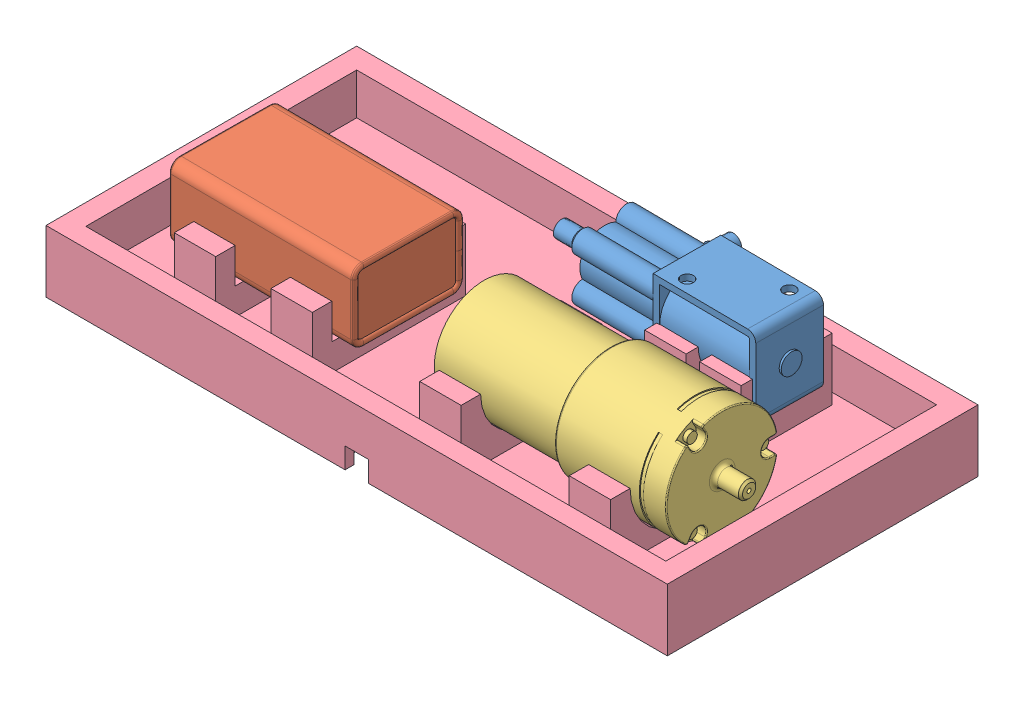
SolidWorks assembly Component_Holder_Assembly, configuration Default. Lengths in mm.
Overall size (150 33.4 75).
4 component instances, 4 part files, 0 mates.
Components (placement in the parent):
- Solenoid-1: Solenoid [Default] at (-18.5853 34.8731 -17.2665) x (0.000076 -1 0.000076) z (0.008726 -0.000076 -0.999962) size (20 56 26.1)
- Studio-R4 CAD Props_Battery-9v-1: Studio-R4 CAD Props_Battery-9v [Default] at (-69.16 35.0714 11.7328) x (0.008726 -0.000076 -0.999962) z (0 1 -0.000076) size (26.6 48.5 17.6)
- model.step-1: model.step [Default] at (6.8477 34.8616 14.5569) x (0 -1 0) z (0 0 1) size (27 65.5 27)
- Component_Holder-2: Component_Holder [Default] at (-129.3978 14.9608 39.05) x (1 0 0) z (0 1 0) size (150 75 20)
